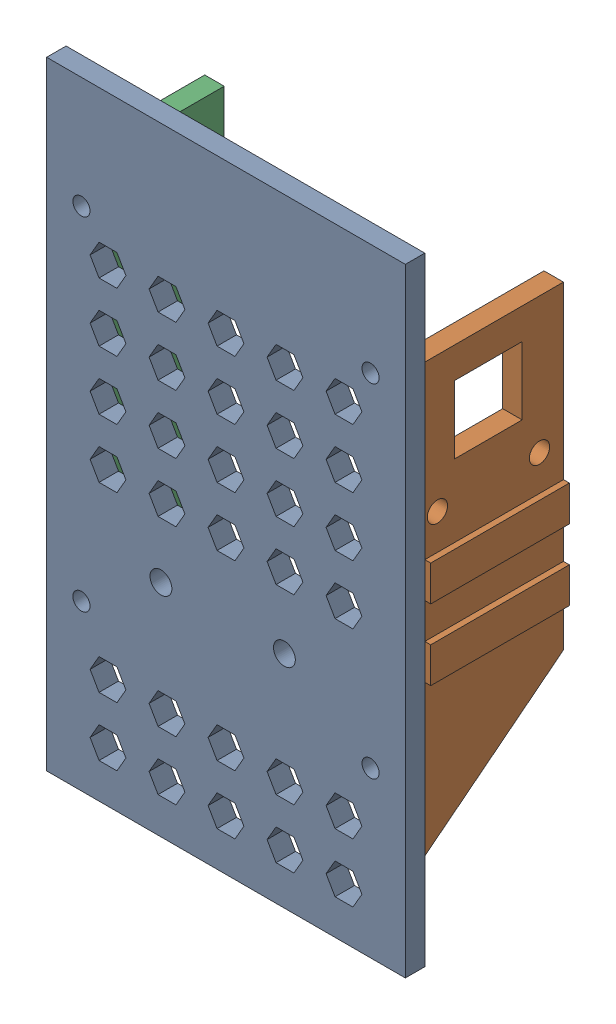
SolidWorks assembly 新新底盤組合建, configuration 預設. Lengths in mm.
Overall size (62.8 104.76 26.8).
3 component instances, 3 part files, 6 mates.
Components (placement in the parent):
- 新新底盤頂面v2-1: 新新底盤頂面v2 [預設] at (-7.2129 1.8553 0) size (60.8 104.76 3.3)
- 新底盤側板右-1: 新底盤側板右 [預設] at (21.2132 11.3295 -10.7877) x (0 0 -1) z (1 0 0) size (23.5 72.49 4.3)
- 新底盤側板-1: 新底盤側板 [預設] at (-32.9868 11.3295 -12.7123) x (0 0 1) z (-1 0 0) size (23.5 74 4.3)
Mates (geometry in assembly coordinates):
- 重合/共線/共點1: coincident anti-aligned: plane of 新新底盤頂面-1 through (-7.2129 1.8553 0) normal (0 0 -1); plane of 新底盤側板-1 through (-25.9868 44.4956 0) normal (0 0 1)
- 重合/共線/共點2: coincident aligned: plane of 新新底盤頂面-1 through (-7.2129 44.4956 3.3) normal (0 1 0); plane of 新底盤側板-1 through (-36.2868 44.4956 -12.7123) normal (0 1 0)
- 重合/共線/共點3: coincident aligned: plane of 新新底盤頂面-1 through (-36.2868 1.8553 3.3) normal (-1 0 0); plane of 新底盤側板-1 through (-36.2868 11.3295 -12.7123) normal (-1 0 0)
- 重合/共線/共點5: coincident: plane of 新新底盤頂面-1 through (-7.2129 44.4956 3.3) normal (0 1 0); plane of 新底盤側板右-1 through (24.5132 44.4956 -10.7877) normal (0 1 0)
- 重合/共線/共點6: coincident aligned: plane of 新新底盤頂面-1 through (24.5132 1.8553 3.3) normal (1 0 0); plane of 新底盤側板右-1 through (24.5132 11.3295 -10.7877) normal (1 0 0)
- 重合/共線/共點7: coincident anti-aligned: plane of 新新底盤頂面-1 through (-7.2129 1.8553 0) normal (0 0 -1); plane of 新底盤側板右-1 through (14.2132 44.4956 0) normal (0 0 1)
